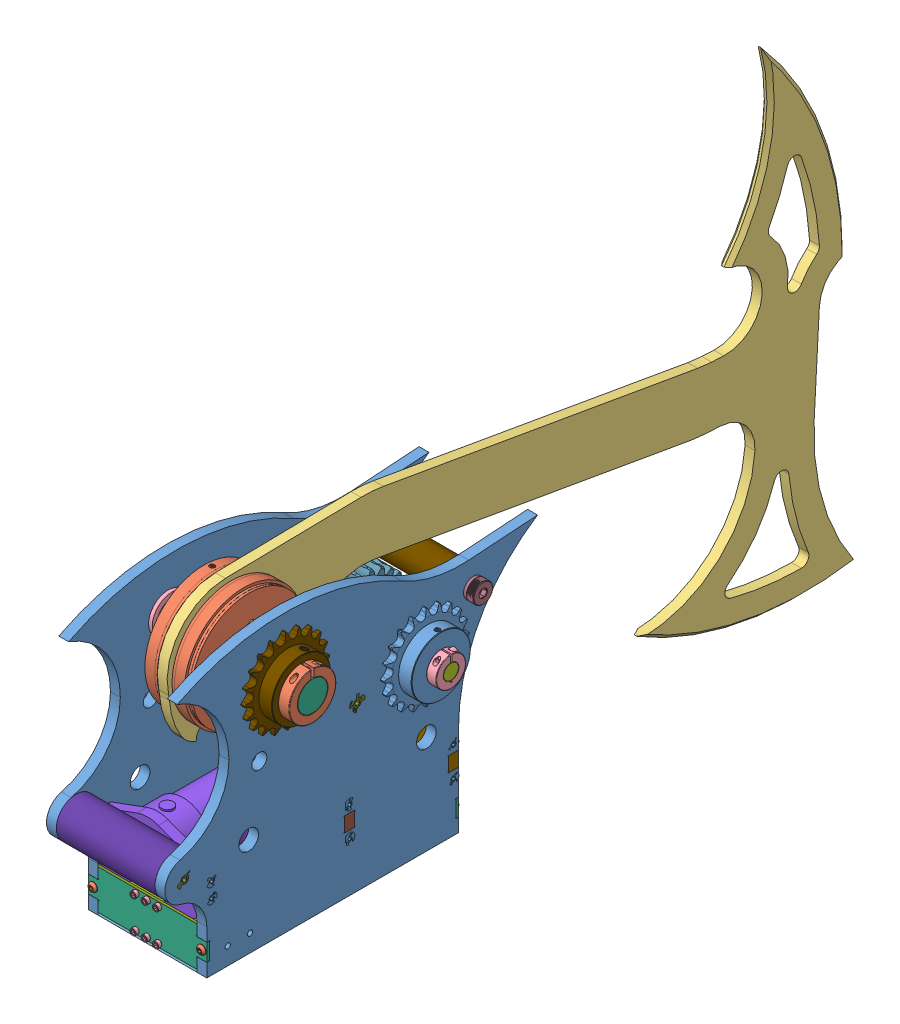
SolidWorks assembly BombshellAxeAsm, configuration Extend. Lengths in mm.
Overall size (220.95 679.92 987.66).
99 component instances, 41 part files, 194 mates.
Components (placement in the parent):
- AxeWeaponRail-1: AxeWeaponRail [Default] at (439.7489 345.0261 495.1514)
- AxeWeaponRail-2: AxeWeaponRail [Default] at (300.0489 345.0261 495.1514)
- AxeArmAsm-1: AxeArmAsm [Default] at (391.7765 573.6147 629.7988) x (0 -0.054175 -0.998531) z (1 0 0) size (901.7 632 77.46)
  - 6524K135 440ftlb Torque Clutch 1500bore-1: 6524K135 440ftlb Torque Clutch 1500bore [6524K135] at (-33.243 17.2859 43.2099) size (152.4 152.56 77.46)
  - AxeBarV2-1: AxeBarV2 [Default] at (-33.243 17.2859 -17.1151) x (0 0 1) z (-1 0 0) size (12.7 632 901.7)
- 6338K442 1500ID Bushing-1: 6338K442 1500ID Bushing [Default] at (434.9864 592.6761 662.0565)
- 6338K442 1500ID Bushing-2: 6338K442 1500ID Bushing [Default] at (317.5114 592.6761 662.0565) x (-1 0 0) z (0 -0.924225 -0.381849)
- AxePodBottom-1: AxePodBottom [Default] at (439.7489 300.5761 752.19) x (0 0 -1) z (1 0 0)
- AxePodFrontRearPlate-1: AxePodFrontRearPlate [Default] at (312.7489 303.7511 428.34)
- AxePodFrontRearPlate-2: AxePodFrontRearPlate [Default] at (312.7489 303.7511 749.015)
- AxePodTop-1: AxePodTop [Default] at (439.7489 354.5511 752.19) x (0 0 -1) z (1 0 0)
- s28400mag-1: s28400mag [Default] at (376.2489 402.1761 739.49) x (0 1 0) z (0 0 -1)
- NanoTech 4S 5000mah 130C pack-1: NanoTech 4S 5000mah 130C pack [Default] at (319.0989 340.7511 599.4047) x (0 0 -1) z (0 -1 0)
- NanoTech 4S 5000mah 130C pack-2: NanoTech 4S 5000mah 130C pack [Default] at (368.0989 340.7511 599.4047) x (0 0 -1) z (0 -1 0)
- MS2-1: MS2 [Default] at (312.7489 313.1491 682.34) x (0 0 1) z (-1 0 0)
- ragebridge2 lpm assembly-1: ragebridge2 lpm assembly [Default] at (323.5439 354.5511 625.19) x (1 0 0) z (0 -1 0) size (105.41 63.5 21.77)
  - heatsink 0002-1: heatsink 0002 [Default] at origin size (93.98 63.5 3.17)
  - ragebridge2 lpm-1: ragebridge2 lpm [Default] at (52.705 25.4 3.175) x (1 0 0) z (0 -1 0) size (105.41 18.6 50.8)
- ragebridge2 lpm assembly-2: ragebridge2 lpm assembly [Default] at (323.5439 303.7511 675.99) x (1 0 0) z (0 1 0) size (105.41 63.5 21.77)
  - heatsink 0002-1: heatsink 0002 [Default] at origin size (93.98 63.5 3.17)
  - ragebridge2 lpm-1: ragebridge2 lpm [Default] at (52.705 25.4 3.175) x (1 0 0) z (0 -1 0) size (105.41 18.6 50.8)
- OrangeRX R410-1: OrangeRX R410 [Default] at (373.9489 346.5511 729.1047)
- 57545K213 24T 6P Worm for 0750 Shaft-1: 57545K213 24T 6P Worm for 0750 Shaft [57545K213] at (376.2489 529.1761 482.4514) x (0 0 -1) z (-1 0 0)
- Gear48T16P_6325K21 MOD FOR LIFTER-1: Gear48T16P_6325K21 MOD FOR LIFTER [Default] at (376.2489 452.9761 559.023) x (0 0 -1) z (1 0 0)
- 57545K227 6P Motor Side Worm for 0875in Shaft-1: 57545K227 6P Motor Side Worm for 0875in Shaft [57545K227] at (376.2489 452.9761 482.4514)
- Gear16T16P_6325K13-1: Gear16T16P_6325K13 [Default] at (376.2489 402.1761 559.023) x (0 0 -1) z (1 0 0)
- 6280K978 Lifter Large Sprocket-1: 6280K978 Lifter Large Sprocket [6280K978] at (463.155 592.6761 662.0565) x (0 -0.288312 -0.957536) z (1 0 0)
- 6280K970 Sprocket 20t Num50 0750Bore-1: 6280K970 Sprocket 20t Num50 0750Bore [6280K97] at (463.155 529.1761 482.4514) x (0 0 -1) z (1 0 0)
- 6157K230 1500in Shaft Collar Alu-2: 6157K230 1500in Shaft Collar Alu [6157K23] at (351.6427 592.6761 662.0565) x (0 0 1) z (-1 0 0)
- 6157K230 1500in Shaft Collar Alu-3: 6157K230 1500in Shaft Collar Alu [6157K23] at (491.3427 592.6761 662.0565) x (0 0 1) z (-1 0 0)
- 6338K431 0750 Bushing-1: 6338K431 0750 Bushing [Default] at (434.9864 529.1761 482.4514) x (-1 0 0) z (0 -0.924225 -0.381849)
- 6338K431 0750 Bushing-2: 6338K431 0750 Bushing [Default] at (317.5114 529.1761 482.4514)
- 6157K160 0750 Shaft Collar-1: 6157K160 0750 Shaft Collar [6157K16] at (490.5489 529.1761 482.4514) x (0 0 1) z (-1 0 0)
- 6157K160 0750 Shaft Collar-2: 6157K160 0750 Shaft Collar [6157K16] at (417.5239 529.1761 482.4514) x (0 0 1) z (-1 0 0)
- 6157K160 0750 Shaft Collar-3: 6157K160 0750 Shaft Collar [6157K16] at (357.1989 529.1761 482.4514) x (0 0 1) z (-1 0 0)
- 6157K160 0750 Shaft Collar-4: 6157K160 0750 Shaft Collar [6157K16] at (290.5239 529.1761 482.4514) x (0 -0.246824 0.96906) z (-1 0 0)
- 6157K230 1500in Shaft Collar Alu-4: 6157K230 1500in Shaft Collar Alu [6157K23] at (289.7302 592.6761 662.0565) x (0 0 -1) z (1 0 0)
- 6157K170 0875 Shaft Collar-2: 6157K170 0875 Shaft Collar [6157K17] at (376.2489 452.9761 520.5514)
- AxeMainShaft-1: AxeMainShaft [Default] at (390.5364 592.6761 662.0565) x (1 0 0) z (0 0.225652 -0.974208)
- AxeChainShaft-1: AxeChainShaft [Default] at (390.5364 529.1761 482.4514) x (1 0 0) z (0 -0.621603 -0.783332)
- LongMagRearMount-1: LongMagRearMount [Default] at (376.2489 357.7261 739.49)
- WormShaftMount1-1: WormShaftMount1 [Default] at (376.2489 357.7261 428.34)
- 2868T195 0875 Sleeve Bushing no flange 1125OD-1: 2868T195 0875 Sleeve Bushing no flange 1125OD [2868T195] at (376.2489 452.9761 441.04)
- WormShaftMount2-1: WormShaftMount2 [Default] at (376.2489 357.7261 562.198)
- 2868T195 0875 Sleeve Bushing no flange 1125OD-2: 2868T195 0875 Sleeve Bushing no flange 1125OD [2868T195] at (376.2489 452.9761 562.198)
- LowerWormShaft-1: LowerWormShaft [Default] at (376.2489 452.9761 495.015) x (0 0 -1) z (1 0 0)
- 6157K170 0875 Shaft Collar-4: 6157K170 0875 Shaft Collar [6157K17] at (376.2489 452.9761 421.99) x (0.927801 -0.373074 0) z (0 0 1)
- 91259A860 0750 Shoulder Bolt for Axe Stop-1: 91259A860 0750 Shoulder Bolt for Axe Stop [91259A860] at (452.4489 564.1011 409.29) x (0 -0.381849 0.924225) z (0 0.924225 0.381849)
- 97135A270 0625-11 Locknut-1: 97135A270 0625-11 Locknut [97135A270] at (300.0489 564.1011 409.29) x (0 1 0) z (0 0 1)
- module standoffs-1: module standoffs [Default] at (312.7489 424.4011 780.765)
- module standoffs-2: module standoffs [Default] at (312.7489 510.1261 558.515)
- 91253A624-1: 91253A624 [91253A624] at (452.4489 510.1261 558.515) x (0 0 -1) z (1 0 0)
- 91253A624-2: 91253A624 [91253A624] at (452.4489 424.4011 780.765) x (0 0 -1) z (1 0 0)
- 91253A624-3: 91253A624 [91253A624] at (300.0489 510.1261 558.515) x (0 0 1) z (-1 0 0)
- 91253A624-4: 91253A624 [91253A624] at (300.0489 424.4011 780.765) x (0 0 1) z (-1 0 0)
- 87235k58 polyurethane tube trimmed to 5in-1: 87235k58 polyurethane tube trimmed to 5in [Default] at (376.2489 424.4011 780.765)
- 9697k158 polyurethane tube trimmed to 5in-1: 9697k158 polyurethane tube trimmed to 5in [Default] at (376.2489 564.1011 409.29)
- 91253A542 0250-20 x 1 FHCS-1: 91253A542 0250-20 x 1 FHCS [91253A542] at (300.0489 405.2646 745.84) x (0 0 1) z (-1 0 0)
- 91253A542 0250-20 x 1 FHCS-2: 91253A542 0250-20 x 1 FHCS [91253A542] at (300.0489 386.2146 745.84) x (0 0 1) z (-1 0 0)
- 91253A542 0250-20 x 1 FHCS-3: 91253A542 0250-20 x 1 FHCS [91253A542] at (300.0489 402.1761 568.548) x (0 0 1) z (-1 0 0)
- 91253A542 0250-20 x 1 FHCS-4: 91253A542 0250-20 x 1 FHCS [91253A542] at (300.0489 364.0761 568.548) x (0 0 1) z (-1 0 0)
- 91253A542 0250-20 x 1 FHCS-5: 91253A542 0250-20 x 1 FHCS [91253A542] at (300.0489 402.1761 434.69) x (0 0 1) z (-1 0 0)
- 91253A542 0250-20 x 1 FHCS-6: 91253A542 0250-20 x 1 FHCS [91253A542] at (300.0489 364.0761 434.69) x (0 0 1) z (-1 0 0)
- 91255A539 0250-20 x 0625 BHCS-1: 91255A539 0250-20 x 0625 BHCS [91255A539] at (306.3989 329.1511 755.5428)
- 91255A539 0250-20 x 0625 BHCS-2: 91255A539 0250-20 x 0625 BHCS [91255A539] at (306.3989 329.1511 424.9872) x (-0.923728 -0.383049 0) z (0 0 -1)
- 91253A542 0250-20 x 1 FHCS-7: 91253A542 0250-20 x 1 FHCS [91253A542] at (452.4489 405.2646 745.84) x (0 0 1) z (1 0 0)
- 91253A542 0250-20 x 1 FHCS-8: 91253A542 0250-20 x 1 FHCS [91253A542] at (452.4489 386.2146 745.84) x (0 0 1) z (1 0 0)
- 91253A542 0250-20 x 1 FHCS-9: 91253A542 0250-20 x 1 FHCS [91253A542] at (452.4489 402.1761 568.548) x (0 0 1) z (1 0 0)
- 91253A542 0250-20 x 1 FHCS-10: 91253A542 0250-20 x 1 FHCS [91253A542] at (452.4489 364.0761 568.548) x (0 0 1) z (1 0 0)
- 91253A542 0250-20 x 1 FHCS-11: 91253A542 0250-20 x 1 FHCS [91253A542] at (452.4489 402.1761 434.69) x (0 0 1) z (1 0 0)
- 91253A542 0250-20 x 1 FHCS-12: 91253A542 0250-20 x 1 FHCS [91253A542] at (452.4489 364.0761 434.69) x (0 0 1) z (1 0 0)
- 91255A539 0250-20 x 0625 BHCS-3: 91255A539 0250-20 x 0625 BHCS [91255A539] at (446.0989 329.1511 755.5428) x (-1 0 0) z (0 0 1)
- 91255A539 0250-20 x 0625 BHCS-4: 91255A539 0250-20 x 0625 BHCS [91255A539] at (446.0989 329.1511 424.9872) x (0.923728 -0.383049 0) z (0 0 -1)
- 3x2 Medium Nutstrip-1: 3x2 Medium Nutstrip [Default] at (357.1989 308.5136 436.2775) x (1 0 0) z (0 1 0)
- 3x2 Medium Nutstrip-2: 3x2 Medium Nutstrip [Default] at (357.1989 349.7886 436.2775) x (1 0 0) z (0 1 0)
- 3x2 Medium Nutstrip-3: 3x2 Medium Nutstrip [Default] at (357.1989 349.7886 744.2525) x (1 0 0) z (0 1 0)
- 3x2 Medium Nutstrip-4: 3x2 Medium Nutstrip [Default] at (357.1989 308.5136 744.2525) x (1 0 0) z (0 1 0)
- 91251A242 10-24 SHCS 0500L-1: 91251A242 10-24 SHCS 0500L [91251A242] at (390.7489 308.5136 739.49) x (-0.923728 -0.383049 0) z (0 0 -1)
- 91253A242 10-24x0500 FHCS-1: 91253A242 10-24x0500 FHCS [91253A242] at (368.9989 300.5761 744.2525) x (1 0 0) z (0 -1 0)
- 91251A242 10-24 SHCS 0500L-2: 91251A242 10-24 SHCS 0500L [91251A242] at (376.2489 308.5136 739.49) x (-0.923728 -0.383049 0) z (0 0 -1)
- 91251A242 10-24 SHCS 0500L-3: 91251A242 10-24 SHCS 0500L [91251A242] at (361.7489 308.5136 739.49) x (-0.923728 -0.383049 0) z (0 0 -1)
- 91251A242 10-24 SHCS 0500L-4: 91251A242 10-24 SHCS 0500L [91251A242] at (390.7489 349.7886 739.49) x (-0.923728 -0.383049 0) z (0 0 -1)
- 91251A242 10-24 SHCS 0500L-5: 91251A242 10-24 SHCS 0500L [91251A242] at (376.2489 349.7886 739.49) x (-0.923728 -0.383049 0) z (0 0 -1)
- 91251A242 10-24 SHCS 0500L-6: 91251A242 10-24 SHCS 0500L [91251A242] at (361.7489 349.7886 739.49) x (-0.923728 -0.383049 0) z (0 0 -1)
- 91251A242 10-24 SHCS 0500L-7: 91251A242 10-24 SHCS 0500L [91251A242] at (368.9989 345.0261 744.2525) x (1 0 0) z (0 -1 0)
- 91251A242 10-24 SHCS 0500L-8: 91251A242 10-24 SHCS 0500L [91251A242] at (383.4989 345.0261 744.2525) x (1 0 0) z (0 -1 0)
- 91251A242 10-24 SHCS 0500L-9: 91251A242 10-24 SHCS 0500L [91251A242] at (390.7489 308.5136 441.04)
- 91251A242 10-24 SHCS 0500L-10: 91251A242 10-24 SHCS 0500L [91251A242] at (376.2489 308.5136 441.04)
- 91251A242 10-24 SHCS 0500L-11: 91251A242 10-24 SHCS 0500L [91251A242] at (361.7489 308.5136 441.04)
- 91251A242 10-24 SHCS 0500L-12: 91251A242 10-24 SHCS 0500L [91251A242] at (390.7489 349.7886 441.04)
- 91251A242 10-24 SHCS 0500L-13: 91251A242 10-24 SHCS 0500L [91251A242] at (376.2489 349.7886 441.04)
- 91251A242 10-24 SHCS 0500L-14: 91251A242 10-24 SHCS 0500L [91251A242] at (361.7489 349.7886 441.04)
- 91251A242 10-24 SHCS 0500L-15: 91251A242 10-24 SHCS 0500L [91251A242] at (368.9989 345.0261 436.2775) x (1 0 0) z (0 -1 0)
- 91251A242 10-24 SHCS 0500L-16: 91251A242 10-24 SHCS 0500L [91251A242] at (383.4989 345.0261 436.2775) x (1 0 0) z (0 -1 0)
- 91253A242 10-24x0500 FHCS-2: 91253A242 10-24x0500 FHCS [91253A242] at (383.4989 300.5761 744.2525) x (1 0 0) z (0 -1 0)
- 91253A242 10-24x0500 FHCS-3: 91253A242 10-24x0500 FHCS [91253A242] at (368.9989 300.5761 436.2775) x (1 0 0) z (0 -1 0)
- 91253A242 10-24x0500 FHCS-4: 91253A242 10-24x0500 FHCS [91253A242] at (383.4989 300.5761 436.2775) x (1 0 0) z (0 -1 0)
- 91253A542 0250-20 x 1 FHCS-13: 91253A542 0250-20 x 1 FHCS [91253A542] at (300.0489 322.8011 696.564) x (0 0 1) z (-1 0 0)
- 91253A542 0250-20 x 1 FHCS-14: 91253A542 0250-20 x 1 FHCS [91253A542] at (300.0489 322.8011 725.266) x (0 0 1) z (-1 0 0)
Mates (geometry in assembly coordinates):
- Distance7: distance = 4.7625 mm anti-aligned: plane of AxeWeaponRail-1 through (439.7489 345.0261 495.1514) normal (-1 0 0); plane of AxeArmAsm-1/6524K135 440ftlb Torque Clutch 1500bore-1 through (434.9864 611.6982 661.0245) normal (1 0 0)
- Coincident64: coincident anti-aligned: plane of AxeWeaponRail-1 through (439.7489 345.0261 495.1514) normal (-1 0 0); plane of 6338K442 1500ID Bushing-1 through (439.7489 592.6761 662.0565) normal (1 0 0)
- Coincident65: coincident anti-aligned: plane of AxeWeaponRail-2 through (312.7489 345.0261 495.1514) normal (1 0 0); plane of 6338K442 1500ID Bushing-2 through (312.7489 592.6761 662.0565) normal (-1 0 0)
- Concentric60: concentric aligned: cylinder of AxeWeaponRail-1 through (439.7489 427.5761 469.7514) axis (1 0 0) radius 12.7; cylinder of AxeWeaponRail-2 through (300.0489 427.5761 469.7514) axis (1 0 0) radius 12.7
- Concentric61: concentric aligned: cylinder of AxeWeaponRail-1 through (439.7489 427.5761 698.3514) axis (1 0 0) radius 12.7; cylinder of AxeWeaponRail-2 through (300.0489 427.5761 698.3514) axis (1 0 0) radius 12.7
- Distance8: distance = 152.4 mm anti-aligned: plane of AxeWeaponRail-2 through (300.0489 345.0261 495.1514) normal (-1 0 0); plane of AxeWeaponRail-1 through (452.4489 345.0261 495.1514) normal (1 0 0)
- Coincident66: coincident anti-aligned: plane of AxeWeaponRail-2 through (312.7489 345.0261 495.1514) normal (1 0 0); plane of AxePodBottom-1 through (312.7489 303.7511 752.19) normal (-1 0 0)
- Coincident67: coincident aligned: plane of AxeWeaponRail-1 through (439.7489 418.1311 428.34) normal (0 0 -1); plane of AxePodBottom-1 through (439.7489 303.7511 428.34) normal (0 0 -1)
- Coincident68: coincident aligned: plane of AxeWeaponRail-1 through (452.4489 300.5761 495.1514) normal (0 -1 0); plane of AxePodBottom-1 through (439.7489 300.5761 752.19) normal (0 -1 0)
- Coincident75: coincident anti-aligned: plane of AxeWeaponRail-1 through (439.7489 345.0261 495.1514) normal (-1 0 0); plane of AxePodTop-1 through (439.7489 357.7261 752.19) normal (1 0 0)
- Coincident77: coincident aligned: plane of AxeWeaponRail-1 through (439.7489 418.1311 428.34) normal (0 0 -1); plane of AxePodTop-1 through (439.7489 357.7261 428.34) normal (0 0 -1)
- Parallel1: parallel aligned: plane of AxeWeaponRail-1 through (439.7489 300.5761 752.19) normal (0 0 1); plane of s28400mag-1 through (376.2489 402.1761 739.49) normal (0 0 1)
- Distance9: distance = 12.7 mm aligned: plane of s28400mag-1 through (376.2489 402.1761 739.49) normal (0 0 1); plane of AxeWeaponRail-1 through (439.7489 300.5761 752.19) normal (0 0 1)
- Distance11: distance = 57.15 mm anti-aligned: cylinder of s28400mag-1 through (376.2489 402.1761 755.492) axis (0 0 -1) radius 6.35; plane of AxeWeaponRail-1 through (439.7489 345.0261 495.1514) normal (-1 0 0)
- Coincident78: coincident aligned: plane of NanoTech 4S 5000mah 130C pack-1 through (368.0989 340.7511 599.4047) normal (0 1 0); plane of NanoTech 4S 5000mah 130C pack-2 through (417.0989 340.7511 599.4047) normal (0 1 0)
- Coincident79: coincident aligned: plane of NanoTech 4S 5000mah 130C pack-1 through (368.0989 340.7511 599.4047) normal (0 0 1); plane of NanoTech 4S 5000mah 130C pack-2 through (417.0989 340.7511 599.4047) normal (0 0 1)
- Coincident80: coincident anti-aligned: plane of NanoTech 4S 5000mah 130C pack-1 through (368.0989 340.7511 599.4047) normal (1 0 0); plane of NanoTech 4S 5000mah 130C pack-2 through (368.0989 340.7511 599.4047) normal (-1 0 0)
- Coincident81: coincident anti-aligned: plane of AxePodBottom-1 through (439.7489 303.7511 752.19) normal (0 1 0); plane of NanoTech 4S 5000mah 130C pack-1 through (368.0989 303.7511 599.4047) normal (0 -1 0)
- Parallel3: parallel anti-aligned: plane of AxeWeaponRail-2 through (312.7489 345.0261 495.1514) normal (1 0 0); plane of NanoTech 4S 5000mah 130C pack-1 through (319.0989 340.7511 599.4047) normal (-1 0 0)
- Distance12: distance = 6.35 mm anti-aligned: plane of AxeWeaponRail-2 through (312.7489 345.0261 495.1514) normal (1 0 0); plane of NanoTech 4S 5000mah 130C pack-1 through (319.0989 340.7511 599.4047) normal (-1 0 0)
- Coincident83: coincident anti-aligned: plane of AxeWeaponRail-2 through (312.7489 345.0261 495.1514) normal (1 0 0); plane of MS2-1 through (312.7489 354.5511 682.34) normal (-1 0 0)
- Coincident85: coincident anti-aligned: plane of AxePodTop-1 through (439.7489 354.5511 752.19) normal (0 -1 0); plane of ragebridge2 lpm assembly-1/heatsink 0002-1 through (421.9689 354.5511 618.205) normal (0 1 0)
- Distance15: distance = 10.795 mm anti-aligned: plane of AxeWeaponRail-1 through (439.7489 345.0261 495.1514) normal (-1 0 0); plane of ragebridge2 lpm assembly-1/ragebridge2 lpm-1 through (428.9539 351.3761 625.19) normal (1 0 0)
- Concentric62: concentric aligned: cylinder of ragebridge2 lpm assembly-1/heatsink 0002-1 through (414.3489 354.5511 679.165) axis (0 -1 0) radius 1.4605; cylinder of ragebridge2 lpm assembly-2/heatsink 0002-1 through (414.3489 306.9261 679.165) axis (0 -1 0) radius 1.4605
- Concentric63: concentric aligned: cylinder of ragebridge2 lpm assembly-1/heatsink 0002-1 through (338.1489 351.3761 622.015) axis (0 1 0) radius 1.4605; cylinder of ragebridge2 lpm assembly-2/heatsink 0002-1 through (338.1489 303.7511 622.015) axis (0 1 0) radius 1.4605
- Distance17: distance = 50.8 mm aligned: plane of ragebridge2 lpm assembly-2/heatsink 0002-1 through (421.9689 303.7511 682.975) normal (0 -1 0); plane of AxePodTop-1 through (439.7489 354.5511 752.19) normal (0 -1 0)
- Coincident89: coincident anti-aligned: plane of AxePodTop-1 through (439.7489 354.5511 752.19) normal (0 -1 0); plane of OrangeRX R410-1 through (373.9489 354.5511 729.1047) normal (0 1 0)
- Distance19: distance = 50.8 mm anti-aligned: plane of OrangeRX R410-1 through (388.9489 354.5511 729.1047) normal (1 0 0); plane of AxeWeaponRail-1 through (439.7489 345.0261 495.1514) normal (-1 0 0)
- Coincident92: coincident anti-aligned: plane of AxePodTop-1 through (439.7489 354.5511 752.19) normal (0 -1 0); plane of MS2-1 through (341.4509 354.5511 682.34) normal (0 1 0)
- Coincident93: coincident aligned: plane of Gear48T16P_6325K21 MOD FOR LIFTER-1 through (376.2489 452.9761 559.023) normal (0 0 1); plane of Gear16T16P_6325K13-1 through (376.2489 402.1761 559.023) normal (0 0 1)
- Distance20: distance = 33.3375 mm: cylinder of Gear48T16P_6325K21 MOD FOR LIFTER-1 through (376.2489 452.9761 533.623) axis (0 0 1) radius 11.1125; cylinder of Gear16T16P_6325K13-1 through (376.2489 402.1761 535.2105) axis (0 0 1) radius 6.35
- Parallel4: parallel anti-aligned: plane of s28400mag-1 through (376.2489 402.1761 566.008) normal (0 0 -1); plane of Gear16T16P_6325K13-1 through (376.2489 402.1761 559.023) normal (0 0 1)
- Concentric65: concentric aligned: cylinder of s28400mag-1 through (376.2489 402.1761 530.448) axis (0 0 1) radius 6.35; cylinder of Gear16T16P_6325K13-1 through (376.2489 402.1761 535.2105) axis (0 0 1) radius 6.35
- Distance21: distance = 9.525 mm anti-aligned: plane of Gear16T16P_6325K13-1 through (376.2489 402.1761 559.023) normal (0 0 1); plane of s28400mag-1 through (376.2489 402.1761 568.548) normal (0 0 -1)
- Concentric66: concentric aligned: cylinder of Gear48T16P_6325K21 MOD FOR LIFTER-1 through (376.2489 452.9761 533.623) axis (0 0 1) radius 11.1125; cylinder of 57545K227 6P Motor Side Worm for 0875in Shaft-1 through (376.2489 452.9761 482.4514) axis (0 0 1) radius 11.1125
- Parallel5: parallel aligned: plane of AxeWeaponRail-1 through (439.7489 345.0261 495.1514) normal (-1 0 0); plane of 57545K227 6P Motor Side Worm for 0875in Shaft-1 through (378.6302 463.1742 448.1299) normal (-1 0 0)
- Coincident95: coincident aligned: plane of Gear48T16P_6325K21 MOD FOR LIFTER-1 through (378.6302 452.9761 533.623) normal (-1 0 0); plane of 57545K227 6P Motor Side Worm for 0875in Shaft-1 through (378.6302 463.1742 448.1299) normal (-1 0 0)
- Coincident96: coincident anti-aligned: plane of 57545K213 24T 6P Worm for 0750 Shaft-1 through (376.2489 529.1761 482.4514) normal (-1 0 0); plane of 57545K227 6P Motor Side Worm for 0875in Shaft-1 through (376.2489 452.9761 482.4514) normal (1 0 0)
- Coincident97: coincident anti-aligned: plane of 57545K213 24T 6P Worm for 0750 Shaft-1; plane of 57545K227 6P Motor Side Worm for 0875in Shaft-1 through (376.2489 452.9761 482.4514) normal (0 0 1)
- Distance22: distance = 76.2 mm anti-aligned: plane of 57545K227 6P Motor Side Worm for 0875in Shaft-1 through (376.2489 452.9761 482.4514) normal (0 1 0); plane of 57545K213 24T 6P Worm for 0750 Shaft-1
- Distance23: distance = 52.3875 mm anti-aligned: cylinder of 57545K227 6P Motor Side Worm for 0875in Shaft-1 through (376.2489 452.9761 482.4514) axis (0 0 1) radius 11.1125; plane of AxeWeaponRail-2 through (312.7489 345.0261 495.1514) normal (1 0 0)
- Concentric67: concentric aligned: cylinder of 6338K442 1500ID Bushing-1 through (473.0864 592.6761 662.0565) axis (-1 0 0) radius 19.05; cylinder of 6280K978 Lifter Large Sprocket-1 through (484.1989 592.6761 662.0565) axis (-1 0 0) radius 19.05
- Distance24: distance = 6.35 mm anti-aligned: plane of AxeWeaponRail-1 through (452.4489 345.0261 495.1514) normal (1 0 0); plane of 6280K978 Lifter Large Sprocket-1 through (458.7989 547.729 675.59) normal (-1 0 0)
- Coincident100: coincident aligned: plane of 6280K978 Lifter Large Sprocket-1 through (458.7989 547.729 675.59) normal (-1 0 0); plane of 6280K970 Sprocket 20t Num50 0750Bore-1 through (458.7989 482.2357 482.4514) normal (-1 0 0)
- Concentric68: concentric anti-aligned: cylinder of AxeWeaponRail-1 through (439.7489 529.1761 482.4514) axis (1 0 0) radius 12.7; cylinder of 6280K970 Sprocket 20t Num50 0750Bore-1 through (484.1989 529.1761 482.4514) axis (-1 0 0) radius 9.525
- Coincident101: coincident aligned: plane of 57545K213 24T 6P Worm for 0750 Shaft-1; plane of 6280K970 Sprocket 20t Num50 0750Bore-1 through (463.155 529.1761 482.4514) normal (0 0 -1)
- Concentric70: concentric anti-aligned: cylinder of 6280K978 Lifter Large Sprocket-1 through (484.1989 592.6761 662.0565) axis (-1 0 0) radius 19.05; cylinder of 6157K230 1500in Shaft Collar Alu-3 through (484.1989 592.6761 662.0565) axis (1 0 0) radius 19.05
- Concentric71: concentric anti-aligned: cylinder of 6280K978 Lifter Large Sprocket-1 through (484.1989 592.6761 662.0565) axis (-1 0 0) radius 19.05; cylinder of 6157K230 1500in Shaft Collar Alu-2 through (344.4989 592.6761 662.0565) axis (1 0 0) radius 19.05
- Coincident102: coincident aligned: circle of AxeArmAsm-1/6524K135 440ftlb Torque Clutch 1500bore-1; plane of 6157K230 1500in Shaft Collar Alu-2 through (358.7864 592.6761 662.0565) normal (1 0 0)
- Coincident103: coincident anti-aligned: plane of 6280K978 Lifter Large Sprocket-1 through (484.1989 592.6761 662.0565) normal (1 0 0); plane of 6157K230 1500in Shaft Collar Alu-3 through (484.1989 592.6761 662.0565) normal (-1 0 0)
- Concentric72: concentric aligned: cylinder of AxeWeaponRail-2 through (300.0489 529.1761 482.4514) axis (1 0 0) radius 12.7; cylinder of 6338K431 0750 Bushing-2 through (301.6364 529.1761 482.4514) axis (1 0 0) radius 12.7
- Concentric73: concentric anti-aligned: cylinder of AxeWeaponRail-2 through (300.0489 529.1761 482.4514) axis (1 0 0) radius 12.7; cylinder of 6338K431 0750 Bushing-1 through (450.8614 529.1761 482.4514) axis (-1 0 0) radius 12.7
- Coincident104: coincident anti-aligned: plane of AxeWeaponRail-1 through (439.7489 345.0261 495.1514) normal (-1 0 0); plane of 6338K431 0750 Bushing-1 through (439.7489 529.1761 482.4514) normal (1 0 0)
- Coincident105: coincident anti-aligned: plane of AxeWeaponRail-2 through (312.7489 345.0261 495.1514) normal (1 0 0); plane of 6338K431 0750 Bushing-2 through (312.7489 529.1761 482.4514) normal (-1 0 0)
- Concentric74: concentric aligned: cylinder of 6338K431 0750 Bushing-2 through (301.6364 529.1761 482.4514) axis (1 0 0) radius 9.5504; cylinder of 6157K160 0750 Shaft Collar-1 through (484.1989 529.1761 482.4514) axis (1 0 0) radius 9.525
- Concentric75: concentric aligned: cylinder of 6157K160 0750 Shaft Collar-1 through (484.1989 529.1761 482.4514) axis (1 0 0) radius 9.525; cylinder of 6157K160 0750 Shaft Collar-2 through (411.1739 529.1761 482.4514) axis (1 0 0) radius 9.525
- Concentric76: concentric aligned: cylinder of 6157K160 0750 Shaft Collar-2 through (411.1739 529.1761 482.4514) axis (1 0 0) radius 9.525; cylinder of 6157K160 0750 Shaft Collar-3 through (350.8489 529.1761 482.4514) axis (1 0 0) radius 9.525
- Concentric77: concentric aligned: cylinder of 6157K160 0750 Shaft Collar-3 through (350.8489 529.1761 482.4514) axis (1 0 0) radius 9.525; cylinder of 6157K160 0750 Shaft Collar-4 through (284.1739 529.1761 482.4514) axis (1 0 0) radius 9.525
- Coincident106: coincident anti-aligned: plane of 6280K970 Sprocket 20t Num50 0750Bore-1 through (484.1989 529.1761 482.4514) normal (1 0 0); plane of 6157K160 0750 Shaft Collar-1 through (484.1989 529.1761 482.4514) normal (-1 0 0)
- Coincident107: coincident anti-aligned: plane of 57545K213 24T 6P Worm for 0750 Shaft-1 through (411.1739 505.3636 482.4514) normal (1 0 0); plane of 6157K160 0750 Shaft Collar-2 through (411.1739 529.1761 482.4514) normal (-1 0 0)
- Coincident108: coincident anti-aligned: plane of 57545K213 24T 6P Worm for 0750 Shaft-1 through (363.5489 474.5872 482.4514) normal (-1 0 0); plane of 6157K160 0750 Shaft Collar-3 through (363.5489 529.1761 482.4514) normal (1 0 0)
- Distance26: distance = 3.175 mm anti-aligned: plane of 6157K160 0750 Shaft Collar-4 through (296.8739 529.1761 482.4514) normal (1 0 0); plane of AxeWeaponRail-2 through (300.0489 345.0261 495.1514) normal (-1 0 0)
- Distance27: distance = 3.175 mm anti-aligned: plane of 6157K230 1500in Shaft Collar Alu-4 through (296.8739 592.6761 662.0565) normal (1 0 0); plane of AxeWeaponRail-2 through (300.0489 345.0261 495.1514) normal (-1 0 0)
- Coincident111: coincident anti-aligned: plane of 57545K227 6P Motor Side Worm for 0875in Shaft-1 through (376.2489 479.0789 514.2014) normal (0 0 1); plane of 6157K170 0875 Shaft Collar-2 through (376.2489 452.9761 514.2014) normal (0 0 -1)
- Coincident113: coincident anti-aligned: circle of 6157K230 1500in Shaft Collar Alu-3; cylinder of AxeMainShaft-1 through (498.4864 592.6761 662.0565) axis (-1 0 0) radius 19.05
- Coincident114: coincident aligned: plane of 6157K230 1500in Shaft Collar Alu-3 through (498.4864 592.6761 662.0565) normal (1 0 0); plane of AxeMainShaft-1 through (498.4864 592.6761 662.0565) normal (1 0 0)
- Coincident115: coincident aligned: plane of 6157K160 0750 Shaft Collar-1 through (496.8989 529.1761 482.4514) normal (1 0 0); plane of AxeChainShaft-1 through (496.8989 529.1761 482.4514) normal (1 0 0)
- Concentric82: concentric anti-aligned: cylinder of 6157K160 0750 Shaft Collar-1 through (484.1989 529.1761 482.4514) axis (1 0 0) radius 9.525; cylinder of AxeChainShaft-1 through (496.8989 529.1761 482.4514) axis (-1 0 0) radius 9.525
- Coincident116: coincident anti-aligned: plane of AxePodTop-1 through (439.7489 357.7261 752.19) normal (0 1 0); plane of LongMagRearMount-1 through (312.7489 357.7261 752.19) normal (0 -1 0)
- Coincident117: coincident anti-aligned: plane of s28400mag-1 through (376.2489 402.1761 739.49) normal (0 0 1); plane of LongMagRearMount-1 through (376.2489 357.7261 739.49) normal (0 0 -1)
- Coincident118: coincident anti-aligned: plane of AxeWeaponRail-2 through (312.7489 345.0261 495.1514) normal (1 0 0); plane of LongMagRearMount-1 through (312.7489 357.7261 752.19) normal (-1 0 0)
- Coincident119: coincident aligned: plane of AxeWeaponRail-2 through (300.0489 418.1311 428.34) normal (0 0 -1); plane of WormShaftMount1-1 through (376.2489 357.7261 428.34) normal (0 0 -1)
- Coincident120: coincident anti-aligned: plane of AxePodTop-1 through (439.7489 357.7261 752.19) normal (0 1 0); plane of WormShaftMount1-1 through (312.7489 357.7261 441.04) normal (0 -1 0)
- Coincident121: coincident anti-aligned: plane of AxeWeaponRail-2 through (312.7489 345.0261 495.1514) normal (1 0 0); plane of WormShaftMount1-1 through (312.7489 357.7261 441.04) normal (-1 0 0)
- Concentric83: concentric anti-aligned: cylinder of WormShaftMount1-1 through (376.2489 452.9761 428.34) axis (0 0 1) radius 14.2875; cylinder of 2868T195 0875 Sleeve Bushing no flange 1125OD-1 through (376.2489 452.9761 453.74) axis (0 0 -1) radius 11.1252
- Coincident122: coincident aligned: plane of WormShaftMount1-1 through (376.2489 357.7261 428.34) normal (0 0 -1); plane of 2868T195 0875 Sleeve Bushing no flange 1125OD-1 through (376.2489 452.9761 428.34) normal (0 0 -1)
- Coincident123: coincident anti-aligned: plane of AxeWeaponRail-2 through (312.7489 345.0261 495.1514) normal (1 0 0); plane of WormShaftMount2-1 through (312.7489 357.7261 574.898) normal (-1 0 0)
- Coincident124: coincident anti-aligned: plane of AxePodTop-1 through (439.7489 357.7261 752.19) normal (0 1 0); plane of WormShaftMount2-1 through (312.7489 357.7261 574.898) normal (0 -1 0)
- Distance28: distance = 6.35 mm aligned: plane of WormShaftMount2-1 through (376.2489 357.7261 562.198) normal (0 0 -1); plane of s28400mag-1 through (376.2489 402.1761 568.548) normal (0 0 -1)
- Coincident125: coincident aligned: plane of WormShaftMount2-1 through (376.2489 357.7261 574.898) normal (0 0 1); plane of 2868T195 0875 Sleeve Bushing no flange 1125OD-2 through (376.2489 452.9761 574.898) normal (0 0 1)
- Concentric84: concentric aligned: cylinder of WormShaftMount2-1 through (376.2489 452.9761 574.898) axis (0 0 -1) radius 14.2875; cylinder of 2868T195 0875 Sleeve Bushing no flange 1125OD-2 through (376.2489 452.9761 574.898) axis (0 0 -1) radius 14.2875
- Concentric85: concentric anti-aligned: cylinder of 2868T195 0875 Sleeve Bushing no flange 1125OD-1 through (376.2489 452.9761 453.74) axis (0 0 -1) radius 11.1252; cylinder of LowerWormShaft-1 through (376.2489 452.9761 415.64) axis (0 0 1) radius 11.1125
- Coincident127: coincident aligned: circle of LowerWormShaft-1; cylinder of 6157K170 0875 Shaft Collar-4 through (376.2489 452.9761 428.34) axis (0 0 -1) radius 11.1125
- Coincident128: coincident anti-aligned: plane of WormShaftMount1-1 through (376.2489 357.7261 428.34) normal (0 0 -1); plane of 6157K170 0875 Shaft Collar-4 through (376.2489 452.9761 428.34) normal (0 0 1)
- Coincident129: coincident aligned: plane of LowerWormShaft-1 through (376.2489 452.9761 415.64) normal (0 0 -1); plane of 6157K170 0875 Shaft Collar-4 through (376.2489 452.9761 415.64) normal (0 0 -1)
- Coincident130: coincident anti-aligned: plane of AxeWeaponRail-1 through (452.4489 345.0261 495.1514) normal (1 0 0); plane of 91259A860 0750 Shoulder Bolt for Axe Stop-1 through (452.4489 564.1011 409.29) normal (-1 0 0)
- Coincident131: coincident anti-aligned: plane of AxeWeaponRail-2 through (300.0489 345.0261 495.1514) normal (-1 0 0); plane of 97135A270 0625-11 Locknut-1 through (300.0489 564.1011 395.5418) normal (1 0 0)
- Concentric87: concentric anti-aligned: circle of 91259A860 0750 Shoulder Bolt for Axe Stop-1; circle of 97135A270 0625-11 Locknut-1
- Distance29: distance = 50.8 mm anti-aligned: plane of AxePodTop-1 through (439.7489 354.5511 752.19) normal (0 -1 0); plane of AxePodBottom-1 through (439.7489 303.7511 752.19) normal (0 1 0)
- Coincident132: coincident anti-aligned: plane of AxeWeaponRail-2 through (312.7489 345.0261 495.1514) normal (1 0 0); plane of AxePodFrontRearPlate-2 through (312.7489 303.7511 752.19) normal (-1 0 0)
- Coincident133: coincident aligned: plane of AxeWeaponRail-2 through (300.0489 300.5761 752.19) normal (0 0 1); plane of AxePodFrontRearPlate-2 through (312.7489 303.7511 752.19) normal (0 0 1)
- Coincident134: coincident anti-aligned: plane of AxePodBottom-1 through (439.7489 303.7511 752.19) normal (0 1 0); plane of AxePodFrontRearPlate-2 through (312.7489 303.7511 752.19) normal (0 -1 0)
- Coincident135: coincident aligned: plane of AxePodFrontRearPlate-1 through (452.4489 340.2636 402.7423) normal (1 0 0); plane of AxePodFrontRearPlate-2 through (452.4489 340.2636 723.4173) normal (1 0 0)
- Coincident137: coincident aligned: plane of AxePodFrontRearPlate-1 through (439.7489 340.2636 402.7423) normal (0 1 0); plane of AxePodFrontRearPlate-2 through (439.7489 340.2636 723.4173) normal (0 1 0)
- Coincident138: coincident aligned: plane of AxeWeaponRail-2 through (300.0489 418.1311 428.34) normal (0 0 -1); plane of AxePodFrontRearPlate-1 through (312.7489 303.7511 428.34) normal (0 0 -1)
- Coincident139: coincident aligned: plane of module standoffs-1 through (312.7489 424.4011 780.765) normal (-1 0 0); plane of module standoffs-2 through (312.7489 510.1261 558.515) normal (-1 0 0)
- Coincident141: coincident anti-aligned: plane of AxeWeaponRail-2 through (312.7489 345.0261 495.1514) normal (1 0 0); plane of module standoffs-1 through (312.7489 424.4011 780.765) normal (-1 0 0)
- Concentric88: concentric aligned: cylinder of AxeWeaponRail-2 through (300.0489 424.4011 780.765) axis (-1 0 0) radius 5.0419; cylinder of module standoffs-1 through (439.7489 424.4011 780.765) axis (-1 0 0) radius 3.9688
- Concentric89: concentric aligned: cylinder of AxeWeaponRail-2 through (300.0489 510.1261 558.515) axis (-1 0 0) radius 5.0419; cylinder of module standoffs-2 through (439.7489 510.1261 558.515) axis (-1 0 0) radius 3.9688
- Coincident142: coincident aligned: plane of 91253A624-1 through (452.4489 505.3636 558.515) normal (1 0 0); plane of 91253A624-2 through (452.4489 419.6386 780.765) normal (1 0 0)
- Coincident143: coincident aligned: plane of 91253A624-3 through (300.0489 505.3636 558.515) normal (-1 0 0); plane of 91253A624-4 through (300.0489 419.6386 780.765) normal (-1 0 0)
- Coincident144: coincident aligned: plane of AxeWeaponRail-1 through (452.4489 345.0261 495.1514) normal (1 0 0); plane of 91253A624-2 through (452.4489 419.6386 780.765) normal (1 0 0)
- Coincident145: coincident aligned: plane of AxeWeaponRail-2 through (300.0489 345.0261 495.1514) normal (-1 0 0); plane of 91253A624-3 through (300.0489 505.3636 558.515) normal (-1 0 0)
- Concentric90: concentric aligned: circle of AxeWeaponRail-2; circle of 91253A624-3
- Concentric91: concentric aligned: circle of AxeWeaponRail-2; circle of 91253A624-4
- Concentric92: concentric anti-aligned: circle of AxeWeaponRail-1; circle of 91253A624-1
- Concentric93: concentric anti-aligned: circle of AxeWeaponRail-1; circle of 91253A624-2
- Coincident146: coincident anti-aligned: plane of AxeWeaponRail-1 through (439.7489 345.0261 495.1514) normal (-1 0 0); plane of 87235k58 polyurethane tube trimmed to 5in-1 through (439.7489 424.4011 780.765) normal (1 0 0)
- Concentric94: concentric aligned: cylinder of module standoffs-1 through (439.7489 424.4011 780.765) axis (-1 0 0) radius 11.1125; cylinder of 87235k58 polyurethane tube trimmed to 5in-1 through (439.7489 424.4011 780.765) axis (-1 0 0) radius 12.7
- Coincident147: coincident anti-aligned: plane of AxeWeaponRail-1 through (439.7489 345.0261 495.1514) normal (-1 0 0); plane of 9697k158 polyurethane tube trimmed to 5in-1 through (439.7489 564.1011 409.29) normal (1 0 0)
- Concentric95: concentric aligned: cylinder of 91259A860 0750 Shoulder Bolt for Axe Stop-1 through (452.4489 564.1011 409.29) axis (-1 0 0) radius 9.525; cylinder of 9697k158 polyurethane tube trimmed to 5in-1 through (439.7489 564.1011 409.29) axis (-1 0 0) radius 9.525
- Coincident148: coincident aligned: plane of 91253A542 0250-20 x 1 FHCS-1 through (300.0489 402.0896 745.84) normal (-1 0 0); plane of 91253A542 0250-20 x 1 FHCS-2 through (300.0489 383.0396 745.84) normal (-1 0 0)
- Coincident149: coincident aligned: plane of 91253A542 0250-20 x 1 FHCS-2 through (300.0489 383.0396 745.84) normal (-1 0 0); plane of 91253A542 0250-20 x 1 FHCS-3 through (300.0489 399.0011 568.548) normal (-1 0 0)
- Coincident150: coincident aligned: plane of 91253A542 0250-20 x 1 FHCS-3 through (300.0489 399.0011 568.548) normal (-1 0 0); plane of 91253A542 0250-20 x 1 FHCS-4 through (300.0489 360.9011 568.548) normal (-1 0 0)
- Coincident151: coincident aligned: plane of 91253A542 0250-20 x 1 FHCS-4 through (300.0489 360.9011 568.548) normal (-1 0 0); plane of 91253A542 0250-20 x 1 FHCS-5 through (300.0489 399.0011 434.69) normal (-1 0 0)
- Coincident152: coincident aligned: plane of 91253A542 0250-20 x 1 FHCS-5 through (300.0489 399.0011 434.69) normal (-1 0 0); plane of 91253A542 0250-20 x 1 FHCS-6 through (300.0489 360.9011 434.69) normal (-1 0 0)
- Coincident153: coincident aligned: plane of AxeWeaponRail-2 through (300.0489 345.0261 495.1514) normal (-1 0 0); plane of 91253A542 0250-20 x 1 FHCS-6 through (300.0489 360.9011 434.69) normal (-1 0 0)
- Concentric96: concentric anti-aligned: circle of AxeWeaponRail-2; circle of 91253A542 0250-20 x 1 FHCS-1
- Concentric97: concentric anti-aligned: circle of AxeWeaponRail-2; circle of 91253A542 0250-20 x 1 FHCS-2
- Concentric98: concentric anti-aligned: circle of AxeWeaponRail-2; circle of 91253A542 0250-20 x 1 FHCS-3
- Concentric99: concentric anti-aligned: circle of AxeWeaponRail-2; circle of 91253A542 0250-20 x 1 FHCS-4
- Concentric100: concentric anti-aligned: circle of AxeWeaponRail-2; circle of 91253A542 0250-20 x 1 FHCS-5
- Concentric101: concentric anti-aligned: circle of AxeWeaponRail-2; circle of 91253A542 0250-20 x 1 FHCS-6
- Concentric102: concentric aligned: cylinder of AxePodFrontRearPlate-2 through (306.3989 329.1511 752.19) axis (0 0 1) radius 3.3782; circle of 91255A539 0250-20 x 0625 BHCS-1
- Coincident154: coincident anti-aligned: plane of AxePodFrontRearPlate-2 through (312.7489 303.7511 752.19) normal (0 0 1); plane of 91255A539 0250-20 x 0625 BHCS-1 through (306.3989 323.6012 752.19) normal (0 0 -1)
- Coincident155: coincident anti-aligned: plane of AxePodFrontRearPlate-1 through (312.7489 303.7511 428.34) normal (0 0 -1); plane of 91255A539 0250-20 x 0625 BHCS-2 through (308.5248 324.0245 428.34) normal (0 0 1)
- Concentric103: concentric aligned: circle of AxePodFrontRearPlate-1; circle of 91255A539 0250-20 x 0625 BHCS-2
- Concentric104: concentric anti-aligned: cylinder of 6157K170 0875 Shaft Collar-2 through (376.2489 452.9761 526.9014) axis (0 0 -1) radius 11.1125; cylinder of LowerWormShaft-1 through (376.2489 452.9761 415.64) axis (0 0 1) radius 11.1125
- Concentric106: concentric aligned: cylinder of 57545K213 24T 6P Worm for 0750 Shaft-1 through (376.2489 529.1761 482.4514) axis (-1 0 0) radius 23.8125; cylinder of AxeChainShaft-1 through (496.8989 529.1761 482.4514) axis (-1 0 0) radius 9.525
- Parallel7: parallel aligned: cylinder of Gear48T16P_6325K21 MOD FOR LIFTER-1 through (376.2489 452.9761 533.623) axis (0 0 1) radius 11.1125; cylinder of LowerWormShaft-1 through (376.2489 452.9761 415.64) axis (0 0 1) radius 11.1125
- Parallel9: parallel aligned: plane of AxePodTop-1 through (439.7489 357.7261 752.19) normal (0 1 0); plane of s28400mag-1 through (376.2489 442.5621 726.79) normal (0 1 0)
- Concentric107: concentric aligned: cylinder of AxeWeaponRail-1 through (452.4489 564.1011 409.29) axis (-1 0 0) radius 9.525; cylinder of 91259A860 0750 Shoulder Bolt for Axe Stop-1 through (452.4489 564.1011 409.29) axis (-1 0 0) radius 9.525
- Coincident156: coincident aligned: plane of 3x2 Medium Nutstrip-1 through (395.2989 313.2761 431.515) normal (0 0 -1); plane of 3x2 Medium Nutstrip-2 through (395.2989 354.5511 431.515) normal (0 0 -1)
- Coincident157: coincident aligned: plane of 3x2 Medium Nutstrip-3 through (395.2989 354.5511 739.49) normal (0 0 -1); plane of 3x2 Medium Nutstrip-4 through (395.2989 313.2761 739.49) normal (0 0 -1)
- Concentric108: concentric anti-aligned: cylinder of AxePodFrontRearPlate-1 through (390.7489 349.7886 431.515) axis (0 0 1) radius 2.5527; cylinder of 3x2 Medium Nutstrip-2 through (390.7489 349.7886 431.515) axis (0 0 -1) radius 2.413
- Concentric109: concentric anti-aligned: cylinder of AxePodFrontRearPlate-1 through (361.7489 349.7886 431.515) axis (0 0 1) radius 2.5527; circle of 3x2 Medium Nutstrip-2
- Concentric110: concentric anti-aligned: cylinder of AxePodFrontRearPlate-1 through (390.7489 308.5136 431.515) axis (0 0 1) radius 2.5527; cylinder of 3x2 Medium Nutstrip-1 through (390.7489 308.5136 431.515) axis (0 0 -1) radius 2.413
- Concentric111: concentric anti-aligned: cylinder of AxePodFrontRearPlate-1 through (361.7489 308.5136 431.515) axis (0 0 1) radius 2.5527; cylinder of 3x2 Medium Nutstrip-1 through (361.7489 308.5136 431.515) axis (0 0 -1) radius 2.413
- Coincident158: coincident anti-aligned: plane of AxePodFrontRearPlate-1 through (312.7489 303.7511 431.515) normal (0 0 1); plane of 3x2 Medium Nutstrip-1 through (395.2989 313.2761 431.515) normal (0 0 -1)
- Concentric112: concentric anti-aligned: cylinder of AxePodFrontRearPlate-1 through (390.7489 349.7886 431.515) axis (0 0 1) radius 2.5527; cylinder of 3x2 Medium Nutstrip-3 through (390.7489 349.7886 739.49) axis (0 0 -1) radius 2.413
- Concentric113: concentric anti-aligned: cylinder of AxePodFrontRearPlate-1 through (390.7489 308.5136 431.515) axis (0 0 1) radius 2.5527; cylinder of 3x2 Medium Nutstrip-4 through (390.7489 308.5136 739.49) axis (0 0 -1) radius 2.413
- Concentric114: concentric anti-aligned: cylinder of AxePodFrontRearPlate-1 through (361.7489 308.5136 431.515) axis (0 0 1) radius 2.5527; cylinder of 3x2 Medium Nutstrip-4 through (361.7489 308.5136 739.49) axis (0 0 -1) radius 2.413
- Concentric115: concentric anti-aligned: cylinder of AxePodFrontRearPlate-1 through (361.7489 349.7886 431.515) axis (0 0 1) radius 2.5527; cylinder of 3x2 Medium Nutstrip-3 through (361.7489 349.7886 739.49) axis (0 0 -1) radius 2.413
- Coincident159: coincident anti-aligned: plane of AxePodFrontRearPlate-2 through (312.7489 303.7511 749.015) normal (0 0 -1); plane of 3x2 Medium Nutstrip-3 through (395.2989 354.5511 749.015) normal (0 0 1)
- Coincident160: coincident aligned: plane of 91251A242 10-24 SHCS 0500L-7 through (368.9989 362.5521 744.2525) normal (0 1 0); plane of 91251A242 10-24 SHCS 0500L-8 through (383.4989 362.5521 744.2525) normal (0 1 0)
- Coincident161: coincident aligned: plane of 91251A242 10-24 SHCS 0500L-15 through (368.9989 362.5521 436.2775) normal (0 1 0); plane of 91251A242 10-24 SHCS 0500L-16 through (383.4989 362.5521 436.2775) normal (0 1 0)
- Coincident162: coincident anti-aligned: plane of AxePodTop-1 through (439.7489 357.7261 752.19) normal (0 1 0); plane of 91251A242 10-24 SHCS 0500L-7 through (368.9989 357.7261 744.2525) normal (0 -1 0)
- Coincident163: coincident anti-aligned: plane of AxePodTop-1 through (439.7489 357.7261 752.19) normal (0 1 0); plane of 91251A242 10-24 SHCS 0500L-16 through (383.4989 357.7261 436.2775) normal (0 -1 0)
- Concentric116: concentric aligned: cylinder of AxePodTop-1 through (368.9989 354.5511 436.2775) axis (0 -1 0) radius 2.5527; cylinder of 91251A242 10-24 SHCS 0500L-15 through (368.9989 362.5521 436.2775) axis (0 -1 0) radius 3.9624
- Concentric117: concentric aligned: cylinder of AxePodTop-1 through (383.4989 354.5511 436.2775) axis (0 -1 0) radius 2.5527; cylinder of 91251A242 10-24 SHCS 0500L-16 through (383.4989 362.5521 436.2775) axis (0 -1 0) radius 3.9624
- Concentric118: concentric aligned: circle of AxePodTop-1; cylinder of 91251A242 10-24 SHCS 0500L-7 through (368.9989 362.5521 744.2525) axis (0 -1 0) radius 3.9624
- Concentric119: concentric aligned: circle of AxePodTop-1; cylinder of 91251A242 10-24 SHCS 0500L-8 through (383.4989 362.5521 744.2525) axis (0 -1 0) radius 3.9624
- Coincident164: coincident aligned: plane of 91251A242 10-24 SHCS 0500L-13 through (376.2489 349.7886 423.514) normal (0 0 -1); plane of 91251A242 10-24 SHCS 0500L-14 through (361.7489 349.7886 423.514) normal (0 0 -1)
- Coincident165: coincident aligned: plane of 91251A242 10-24 SHCS 0500L-12 through (390.7489 349.7886 423.514) normal (0 0 -1); plane of 91251A242 10-24 SHCS 0500L-13 through (376.2489 349.7886 423.514) normal (0 0 -1)
- Coincident166: coincident aligned: plane of 91251A242 10-24 SHCS 0500L-11 through (361.7489 308.5136 423.514) normal (0 0 -1); plane of 91251A242 10-24 SHCS 0500L-12 through (390.7489 349.7886 423.514) normal (0 0 -1)
- Coincident167: coincident aligned: plane of 91251A242 10-24 SHCS 0500L-10 through (376.2489 308.5136 423.514) normal (0 0 -1); plane of 91251A242 10-24 SHCS 0500L-11 through (361.7489 308.5136 423.514) normal (0 0 -1)
- Coincident168: coincident aligned: plane of 91251A242 10-24 SHCS 0500L-9 through (390.7489 308.5136 423.514) normal (0 0 -1); plane of 91251A242 10-24 SHCS 0500L-10 through (376.2489 308.5136 423.514) normal (0 0 -1)
- Coincident169: coincident aligned: plane of 91251A242 10-24 SHCS 0500L-1 through (390.7489 308.5136 757.016) normal (0 0 1); plane of 91251A242 10-24 SHCS 0500L-2 through (376.2489 308.5136 757.016) normal (0 0 1)
- Coincident170: coincident aligned: plane of 91251A242 10-24 SHCS 0500L-2 through (376.2489 308.5136 757.016) normal (0 0 1); plane of 91251A242 10-24 SHCS 0500L-3 through (361.7489 308.5136 757.016) normal (0 0 1)
- Coincident171: coincident aligned: plane of 91251A242 10-24 SHCS 0500L-3 through (361.7489 308.5136 757.016) normal (0 0 1); plane of 91251A242 10-24 SHCS 0500L-4 through (390.7489 349.7886 757.016) normal (0 0 1)
- Coincident172: coincident aligned: plane of 91251A242 10-24 SHCS 0500L-4 through (390.7489 349.7886 757.016) normal (0 0 1); plane of 91251A242 10-24 SHCS 0500L-5 through (376.2489 349.7886 757.016) normal (0 0 1)
- Coincident173: coincident aligned: plane of 91251A242 10-24 SHCS 0500L-5 through (376.2489 349.7886 757.016) normal (0 0 1); plane of 91251A242 10-24 SHCS 0500L-6 through (361.7489 349.7886 757.016) normal (0 0 1)
- Coincident174: coincident anti-aligned: plane of AxePodFrontRearPlate-2 through (312.7489 303.7511 752.19) normal (0 0 1); plane of 91251A242 10-24 SHCS 0500L-6 through (361.7489 349.7886 752.19) normal (0 0 -1)
- Concentric120: concentric anti-aligned: cylinder of AxePodFrontRearPlate-2 through (361.7489 349.7886 752.19) axis (0 0 1) radius 2.5527; cylinder of 91251A242 10-24 SHCS 0500L-6 through (361.7489 349.7886 757.016) axis (0 0 -1) radius 3.9624
- Concentric121: concentric anti-aligned: cylinder of AxePodFrontRearPlate-2 through (376.2489 349.7886 752.19) axis (0 0 1) radius 2.5527; cylinder of 91251A242 10-24 SHCS 0500L-5 through (376.2489 349.7886 757.016) axis (0 0 -1) radius 3.9624
- Concentric122: concentric anti-aligned: cylinder of AxePodFrontRearPlate-2 through (390.7489 349.7886 752.19) axis (0 0 1) radius 2.5527; cylinder of 91251A242 10-24 SHCS 0500L-4 through (390.7489 349.7886 757.016) axis (0 0 -1) radius 3.9624
- Concentric123: concentric anti-aligned: cylinder of AxePodFrontRearPlate-2 through (361.7489 308.5136 752.19) axis (0 0 1) radius 2.5527; cylinder of 91251A242 10-24 SHCS 0500L-3 through (361.7489 308.5136 757.016) axis (0 0 -1) radius 3.9624
- Concentric124: concentric anti-aligned: circle of AxePodFrontRearPlate-2; cylinder of 91251A242 10-24 SHCS 0500L-2 through (376.2489 308.5136 757.016) axis (0 0 -1) radius 3.9624
- Concentric125: concentric anti-aligned: cylinder of AxePodFrontRearPlate-2 through (390.7489 308.5136 752.19) axis (0 0 1) radius 2.5527; cylinder of 91251A242 10-24 SHCS 0500L-1 through (390.7489 308.5136 757.016) axis (0 0 -1) radius 3.9624
- Concentric126: concentric anti-aligned: circle of AxePodFrontRearPlate-1; cylinder of 91251A242 10-24 SHCS 0500L-14 through (361.7489 349.7886 423.514) axis (0 0 1) radius 3.9624
- Concentric127: concentric anti-aligned: circle of AxePodFrontRearPlate-1; cylinder of 91251A242 10-24 SHCS 0500L-13 through (376.2489 349.7886 423.514) axis (0 0 1) radius 3.9624
- Concentric128: concentric anti-aligned: circle of AxePodFrontRearPlate-1; cylinder of 91251A242 10-24 SHCS 0500L-12 through (390.7489 349.7886 423.514) axis (0 0 1) radius 3.9624
- Concentric129: concentric anti-aligned: circle of AxePodFrontRearPlate-1; cylinder of 91251A242 10-24 SHCS 0500L-11 through (361.7489 308.5136 423.514) axis (0 0 1) radius 3.9624
- Concentric130: concentric anti-aligned: circle of AxePodFrontRearPlate-1; cylinder of 91251A242 10-24 SHCS 0500L-10 through (376.2489 308.5136 423.514) axis (0 0 1) radius 3.9624
- Concentric131: concentric anti-aligned: circle of AxePodFrontRearPlate-1; cylinder of 91251A242 10-24 SHCS 0500L-9 through (390.7489 308.5136 423.514) axis (0 0 1) radius 3.9624
- Coincident175: coincident anti-aligned: plane of AxePodFrontRearPlate-1 through (312.7489 303.7511 428.34) normal (0 0 -1); plane of 91251A242 10-24 SHCS 0500L-9 through (390.7489 308.5136 428.34) normal (0 0 1)
- Coincident176: coincident aligned: plane of 91253A242 10-24x0500 FHCS-1 through (368.9989 300.5761 741.8395) normal (0 -1 0); plane of 91253A242 10-24x0500 FHCS-2 through (383.4989 300.5761 741.8395) normal (0 -1 0)
- Coincident177: coincident aligned: plane of 91253A242 10-24x0500 FHCS-2 through (383.4989 300.5761 741.8395) normal (0 -1 0); plane of 91253A242 10-24x0500 FHCS-3 through (368.9989 300.5761 433.8645) normal (0 -1 0)
- Coincident178: coincident aligned: plane of 91253A242 10-24x0500 FHCS-3 through (368.9989 300.5761 433.8645) normal (0 -1 0); plane of 91253A242 10-24x0500 FHCS-4 through (383.4989 300.5761 433.8645) normal (0 -1 0)
- Coincident179: coincident aligned: plane of AxePodBottom-1 through (439.7489 300.5761 752.19) normal (0 -1 0); plane of 91253A242 10-24x0500 FHCS-1 through (368.9989 300.5761 741.8395) normal (0 -1 0)
- Concentric132: concentric anti-aligned: cylinder of AxePodBottom-1 through (383.4989 303.7511 436.2775) axis (0 1 0) radius 2.5527; circle of 91253A242 10-24x0500 FHCS-4
- Concentric133: concentric anti-aligned: cylinder of AxePodBottom-1 through (368.9989 303.7511 436.2775) axis (0 1 0) radius 2.5527; circle of 91253A242 10-24x0500 FHCS-3
- Concentric134: concentric aligned: circle of AxePodBottom-1; circle of 91253A242 10-24x0500 FHCS-2
- Concentric135: concentric aligned: circle of AxePodBottom-1; circle of 91253A242 10-24x0500 FHCS-1
- Coincident180: coincident aligned: plane of 91253A542 0250-20 x 1 FHCS-13 through (300.0489 319.6261 696.564) normal (-1 0 0); plane of 91253A542 0250-20 x 1 FHCS-14 through (300.0489 319.6261 725.266) normal (-1 0 0)
- Coincident181: coincident aligned: plane of AxeWeaponRail-2 through (300.0489 345.0261 495.1514) normal (-1 0 0); plane of 91253A542 0250-20 x 1 FHCS-14 through (300.0489 319.6261 725.266) normal (-1 0 0)
- Concentric136: concentric anti-aligned: cylinder of AxeWeaponRail-2 through (312.7489 322.8011 696.564) axis (1 0 0) radius 3.3782; circle of 91253A542 0250-20 x 1 FHCS-13
- Concentric137: concentric anti-aligned: cylinder of AxeWeaponRail-2 through (312.7489 322.8011 725.266) axis (1 0 0) radius 3.3782; circle of 91253A542 0250-20 x 1 FHCS-14
- Distance30: distance = 12.7 mm aligned: plane of MS2-1 through (312.7489 354.5511 739.49) normal (0 0 1); plane of AxeWeaponRail-2 through (300.0489 300.5761 752.19) normal (0 0 1)
- Concentric138: concentric anti-aligned: cylinder of 6338K442 1500ID Bushing-2 through (279.4114 592.6761 662.0565) axis (1 0 0) radius 19.05; cylinder of AxeMainShaft-1 through (498.4864 592.6761 662.0565) axis (-1 0 0) radius 19.05
- Concentric139: concentric aligned: cylinder of 6157K230 1500in Shaft Collar Alu-4 through (296.8739 592.6761 662.0565) axis (-1 0 0) radius 19.05; cylinder of AxeMainShaft-1 through (498.4864 592.6761 662.0565) axis (-1 0 0) radius 19.05
- Concentric140: concentric anti-aligned: cylinder of AxeArmAsm-1/6524K135 440ftlb Torque Clutch 1500bore-1 through (434.9864 592.6761 662.0565) axis (1 0 0) radius 19.05; cylinder of AxeMainShaft-1 through (498.4864 592.6761 662.0565) axis (-1 0 0) radius 19.05
- Parallel10: parallel anti-aligned: cylinder of AxeWeaponRail-2 through (300.0489 592.6761 662.0565) axis (1 0 0) radius 22.225; cylinder of AxeMainShaft-1 through (498.4864 592.6761 662.0565) axis (-1 0 0) radius 19.05
- Concentric143: concentric anti-aligned: cylinder of AxeWeaponRail-2 through (300.0489 592.6761 662.0565) axis (1 0 0) radius 22.225; cylinder of AxeMainShaft-1 through (498.4864 592.6761 662.0565) axis (-1 0 0) radius 19.05
